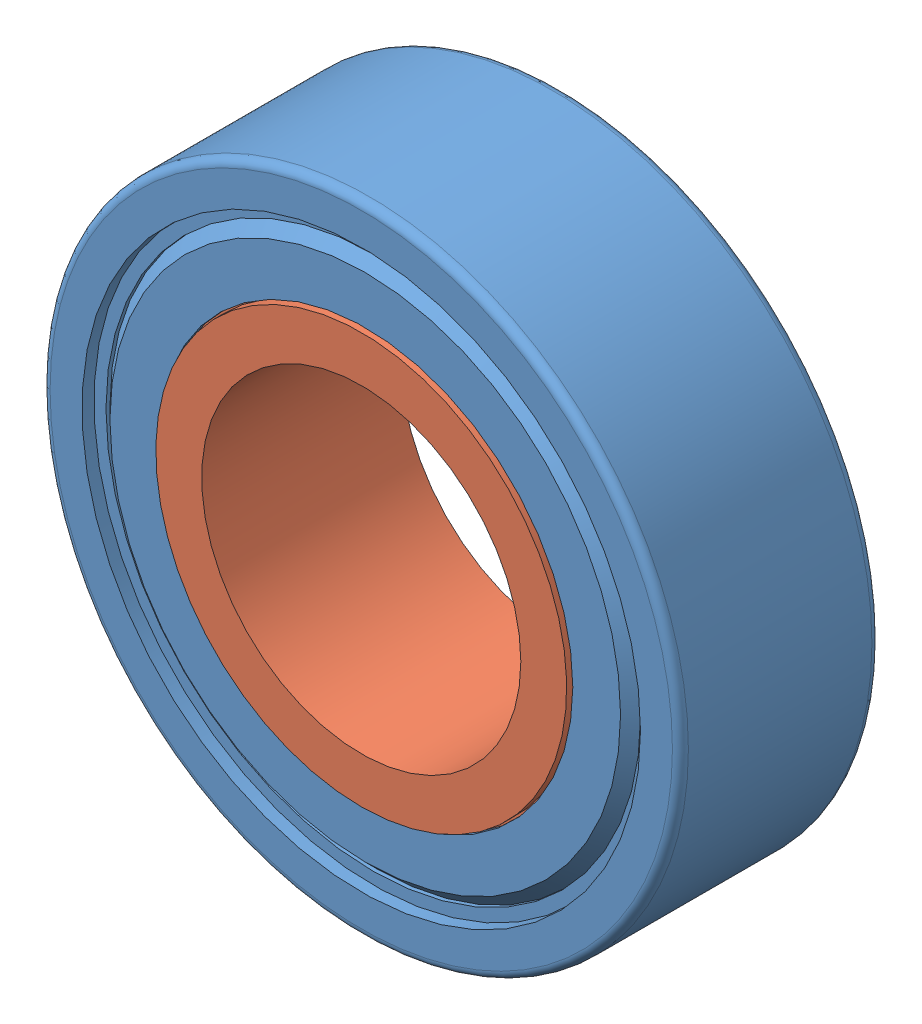
SolidWorks assembly 688ZZ Bearing Assembly, configuration Default. Lengths in mm.
Overall size (17.99 17.98 5).
13 component instances, 4 part files, 5 mates.
Components (placement in the parent):
- Outer Ring-1: Outer Ring [Default] at origin size (16 16 5)
- Inner Ring-1: Inner Ring [Default] x (-0.241565 -0.970385 0) z (0 0 1) size (10.6 10.6 5)
- Cage-1: Cage [Default] x (0.535517 0.844524 0) z (0 0 1) size (13.01 13.06 2.21)
- 2mm Ball Bearing-1: 2mm Ball Bearing [Default] at (-5.0671 3.2131 0) x (0.050652 0.835774 0.546732) z (0.977207 -0.154478 0.145614) size (2 2 2)
- 2mm Ball Bearing-2: 2mm Ball Bearing [Default] at (-5.988 -0.3789 0) x (-0.450278 0.705928 0.546732) z (0.881377 0.449412 0.145614) size (2 2 2)
- 2mm Ball Bearing-3: 2mm Ball Bearing [Default] at (-4.6217 -3.8262 0) x (-0.779216 0.306441 0.546732) z (0.448891 0.881642 0.145614) size (2 2 2)
- 2mm Ball Bearing-4: 2mm Ball Bearing [Default] at (-1.49 -5.812 0) x (-0.810521 -0.210096 0.546732) z (-0.155056 0.977115 0.145614) size (2 2 2)
- 2mm Ball Bearing-5: 2mm Ball Bearing [Default] at (2.2108 -5.5778 0) x (-0.532234 -0.646383 0.546732) z (-0.699777 0.699363 0.145614) size (2 2 2)
- 2mm Ball Bearing-6: 2mm Ball Bearing [Default] at (5.0671 -3.2131 0) x (-0.050652 -0.835774 0.546732) z (-0.977207 0.154478 0.145614) size (2 2 2)
- 2mm Ball Bearing-7: 2mm Ball Bearing [Default] at (5.988 0.3789 0) x (0.450278 -0.705928 0.546732) z (-0.881377 -0.449412 0.145614) size (2 2 2)
- 2mm Ball Bearing-8: 2mm Ball Bearing [Default] at (4.6217 3.8262 0) x (0.779216 -0.306441 0.546732) z (-0.448891 -0.881642 0.145614) size (2 2 2)
- 2mm Ball Bearing-9: 2mm Ball Bearing [Default] at (1.49 5.812 0) x (0.810521 0.210096 0.546732) z (0.155056 -0.977115 0.145614) size (2 2 2)
- 2mm Ball Bearing-10: 2mm Ball Bearing [Default] at (-2.2108 5.5778 0) x (0.532234 0.646383 0.546732) z (0.699777 -0.699363 0.145614) size (2 2 2)
Mates (geometry in assembly coordinates):
- Concentric1: concentric aligned: cylinder of Outer Ring-1 through (0 0 6.7554) axis (0 0 1) radius 6.7; circle of Cage-1
- Tangent13: tangent anti-aligned: torus of Outer Ring-1; sphere of 2mm Ball Bearing-1
- Concentric2: concentric: sphere of assembly; point of Cage-1; sphere of 2mm Ball Bearing-1
- Tangent14: tangent anti-aligned: torus of Inner Ring-1; sphere of 2mm Ball Bearing-1
- Concentric3: concentric aligned: cylinder of Outer Ring-1 through (0 0 6.7554) axis (0 0 1) radius 5.2029; cylinder of Inner Ring-1 through (0 0 6.7554) axis (0 0 1) radius 5.3
